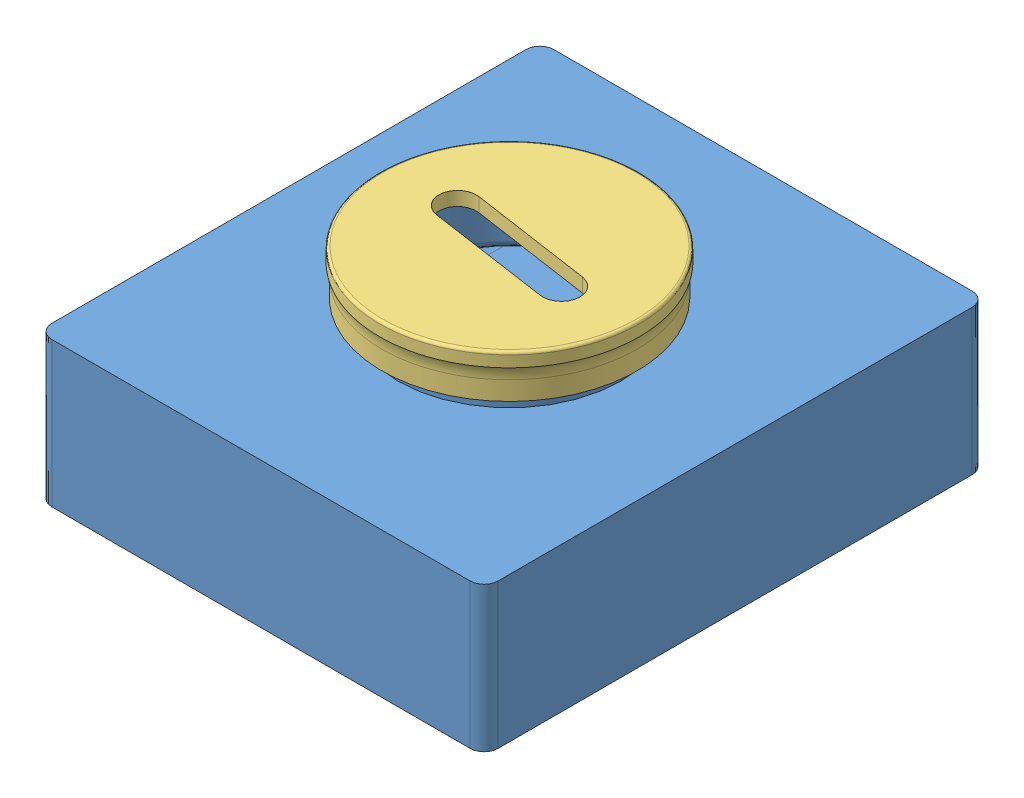
SolidWorks assembly Model Sailboat external enclosure Assembly 5.18.18, configuration Default. Lengths in mm.
Overall size (203.2 93.98 228.6).
4 component instances, 4 part files, 6 mates.
Components (placement in the parent):
- Model Sailboat internal enclosure-1: Model Sailboat internal enclosure [Default] at (175.6992 196.6233 340.5165) size (203.2 85.09 228.6)
- Enclosure O-Ring-1: Enclosure O-Ring [Default] at (121.2364 263.1713 325.8104) x (0.799081 0 0.601223) z (-0.601223 0 0.799081) size (114.62 1.59 114.62)
- External enclosure cap 5.18.18-2: External enclosure cap 5.18.18 [Default] at (121.2364 263.9333 325.8104) x (-0.989379 0 -0.145362) z (0.145362 0 -0.989379) size (118.11 20.32 118.11)
- External enclosure fitting 5.16.18-2: External enclosure fitting 5.16.18 [Default] at (171.6197 263.8063 351.1873) x (0.979496 0 0.201465) z (0 1 0) size (114.27 114.7 15.44)
Mates (geometry in assembly coordinates):
- Lock1: lock: unknown of Model Sailboat internal enclosure-1
- Coincident1: coincident anti-aligned: plane of Model Sailboat internal enclosure-1 through (121.2364 275.3633 325.8104) normal (0 1 0); plane of External enclosure fitting 5.16.18-2 through (121.2364 275.3633 325.8104) normal (0 -1 0)
- Concentric1: concentric anti-aligned: circle of Model Sailboat internal enclosure-1; circle of External enclosure fitting 5.16.18-2
- Concentric2: concentric aligned: circle of Model Sailboat internal enclosure-1; circle of External enclosure cap 5.18.18-2
- Lock2: lock: unknown of Model Sailboat internal enclosure-1; unknown of Enclosure O-Ring-1
- LimitDistance1: limit distance = 0 mm anti-aligned: plane of External enclosure cap 5.18.18-2 through (121.2364 277.9033 325.8104) normal (0 -1 0); plane of External enclosure fitting 5.16.18-2 through (121.2364 277.9033 325.8104) normal (0 1 0)
